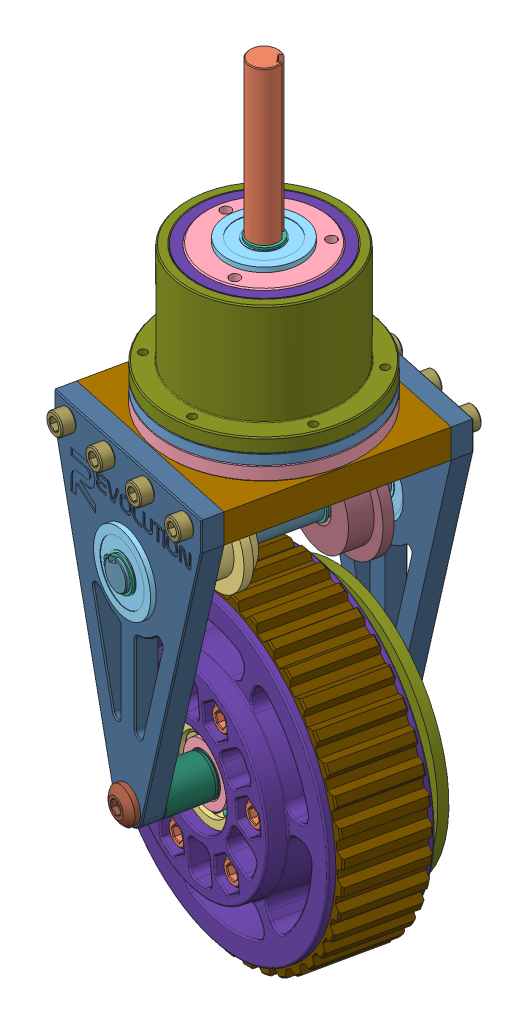
SolidWorks assembly Revolution 2 Plaction, configuration Default. Lengths in mm.
Overall size (163.7 274.4 125.67).
90 component instances, 35 part files, 0 mates.
Components (placement in the parent):
- cs_drive_hub_asm_1-1: cs_drive_hub_asm_1 [Default] at (28.1074 158.1318 104.3172) x (-0.796969 0 0.60402) z (-0.60402 0 -0.796969) size (89.7 127.05 89.7)
  - 5906K526_thrust_bushing_1-1: 5906K526_thrust_bushing_1 [Default] at (33.9501 -89.5224 3.5116) x (-0.279506 0 -0.960144) z (0 -1 0) size (63.5 63.5 3.17)
  - cs_vert_drive_shaft_1-1: cs_vert_drive_shaft_1 [Default] at (390.5574 -784.499 -2.4616) x (0 1 0) z (0.016748 0 0.99986) size (127.05 9.26 9.53)
  - 6843K12_miter_gear_1-1: 6843K12_miter_gear_1 [Default] at (36.0118 -122.8345 2.5948) x (-0.91373 0 0.406323) z (-0.406323 0 -0.91373) size (27.69 19.05 27.69)
  - revo2_pivot_hub-1: revo2_pivot_hub [Default] at (32.6196 -72.4841 4.7196) x (-0.740355 0 0.672216) z (-0.672216 0 -0.740355) size (63.5 46.42 63.5)
  - brf-06_1-1: brf-06_1 [Default] at (33.9501 -95.4787 3.5116) x (-0.582551 0 0.812794) z (0 -1 0) size (24.59 24.59 7.11)
  - brf-06_1-2: brf-06_1 [Default] at (33.9501 -53.0226 3.5116) x (-0.999614 0 -0.027772) z (0 1 0) size (24.59 24.59 7.11)
  - Imported_1-1: Imported_1 [Default] at (33.9501 -123.279 3.5116) x (0 -1 0) z (0.051397 0 0.998678) size (0.64 12.09 10.6)
  - Imported_1-2: Imported_1 [Default] at (33.9501 -49.0094 3.5116) x (0 1 0) z (0.82628 0 -0.563259) size (0.64 12.09 10.6)
  - large_thrust_bushing_1-1: large_thrust_bushing_1 [Default] at (33.9501 -102.2097 3.5116) x (1 0 0) z (0 -1 0) size (19.05 19.05 1.57)
  - bushing_backer_1-1: bushing_backer_1 [Default] at (33.9501 -99.0347 3.5116) x (1 0 0) z (0 -1 0) size (25.4 25.4 3.17)
- cs_wheel_box_asm_plaction-1: cs_wheel_box_asm_plaction [Default] at (-5.7354 51.1469 144.7113) x (0.977946 0 0.20886) z (0 1 0) size (149.25 84.94 179.3)
  - revo2_wheel_box_cap-1: revo2_wheel_box_cap [Default] at origin size (63.5 63.5 9.53)
  - 6843K12_miter_gear_1-1: 6843K12_miter_gear_1 [Default] at (1.3308 15.2099 -25.4535) x (-0.668029 0 0.744136) z (0.744136 0 0.668029) size (27.69 19.05 27.69)
  - revo2_side_plate-1: revo2_side_plate [Default] at (-18.57 61.2601 -1.4632) x (1 0 0) z (0 -1 0) size (63.5 106.45 6.35)
  - revo2_side_plate-2: revo2_side_plate [Default] at (18.217 -14.9399 -1.4632) x (-1 0 0) z (0 1 0) size (63.5 106.45 6.35)
  - BHCS_91255A535-1: BHCS_91255A535 [Default] at (-0.1765 -14.9399 -90.5764) x (1 0 0) z (0 -1 0) size (11.23 11.23 13.63)
  - 91251A192_shcs-1: 91251A192_shcs [Default] at (-25.5765 51.7351 4.7625) x (1 0 0) z (0 -1 0) size (6.86 6.86 13.9)
  - 91251A192_shcs-2: 91251A192_shcs [Default] at (25.2235 51.7351 4.7625) x (1 0 0) z (0 -1 0) size (6.86 6.86 13.9)
  - 91251A192_shcs-3: 91251A192_shcs [Default] at (-8.6423 51.7351 4.7665) x (1 0 0) z (0 -1 0) size (6.86 6.86 13.9)
  - 91251A192_shcs-4: 91251A192_shcs [Default] at (8.2893 -5.4149 4.7665) x (1 0 0) z (0 1 0) size (6.86 6.86 13.9)
  - 91251A192_shcs-5: 91251A192_shcs [Default] at (-25.5765 -5.4149 4.7625) x (1 0 0) z (0 1 0) size (6.86 6.86 13.9)
  - 91251A192_shcs-6: 91251A192_shcs [Default] at (25.2235 -5.4149 4.7625) x (1 0 0) z (0 1 0) size (6.86 6.86 13.9)
  - brf-06_1-1: brf-06_1 [Default] at (-0.1765 59.2789 -23.7744) x (1 0 0) z (0 1 0) size (24.59 24.59 7.11)
  - brf-06_1-2: brf-06_1 [Default] at (-0.1765 -12.9587 -23.7744) x (0.755419 0 -0.655243) z (0 -1 0) size (24.59 24.59 7.11)
  - 16t_ws_globe_gear-1: 16t_ws_globe_gear [Default] at (2.3218 39.2687 -25.5275) x (0.818565 0 -0.574414) z (0.574414 0 0.818565) size (35.31 10.29 35.31)
  - revo2_cross_drive_shaft-1: revo2_cross_drive_shaft [Default] at (136.4364 723.0009 -354.9485) x (0 -1 0) z (-0.924435 0 -0.381339) size (83.39 9.26 9.53)
  - Imported_1-1: Imported_1 [Default] at (-0.1765 -16.9719 -23.7744) x (0 1 0) z (0 0 1) size (0.64 12.09 10.6)
  - Imported_1-2: Imported_1 [Default] at (-0.1765 63.4318 -23.7744) x (0 -1 0) z (0 0 1) size (0.64 12.09 10.6)
  - large_thrust_bushing_1-1: large_thrust_bushing_1 [Default] at (-0.1765 -5.4149 -23.7744) x (1 0 0) z (0 1 0) size (19.05 19.05 1.57)
  - 91251A192_shcs-7: 91251A192_shcs [Default] at (8.2893 51.7351 4.7645) x (1 0 0) z (0 -1 0) size (6.86 6.86 13.9)
  - 91251A192_shcs-8: 91251A192_shcs [Default] at (-8.6423 -5.4149 4.7645) x (1 0 0) z (0 1 0) size (6.86 6.86 13.9)
  - Imported_1-3: Imported_1 [Default] at (-0.1765 15.6544 -23.7744) x (0 -1 0) z (0 0 1) size (0.64 12.09 10.6)
  - Imported_1-4: Imported_1 [Default] at (-0.1765 48.5474 -23.7744) x (0 -1 0) z (0 0 1) size (0.64 12.09 10.6)
  - Imported_1-5: Imported_1 [Default] at (-0.1765 37.3714 -23.7744) x (0 1 0) z (0 0 1) size (0.64 12.09 10.6)
  - BHCS_91255A535-2: BHCS_91255A535 [Default] at (-0.1765 61.2601 -90.5764) x (0.396029 0 -0.918238) z (0 1 0) size (11.23 11.23 13.63)
  - revo2_wheel_shaft-1: revo2_wheel_shaft [Default] at (-0.1765 -8.5899 -90.5764) x (0.571408 0 0.820666) z (0 1 0) size (12.7 12.7 63.5)
  - AM_36t_sprocket-1: AM_36t_sprocket [Default] at (-0.1765 48.1029 -90.5764) x (0.524782 0 0.851237) z (0 -1 0) size (82.55 82.55 3.1)
  - 4Plaction-500bearing-1: 4Plaction-500bearing [Default] at (-0.1765 3.3481 -90.5764) x (0 1 0) z (-0.599972 0 0.800021) size (41.66 115.7 115.7)
    - 4MW_d011-1: 4MW_d011 [Default] at origin size (22.87 98.05 98.05)
    - 4MW_d011-2: 4MW_d011 [Default] at (41.656 0 0) x (-1 0 0) z (0 0 -1) size (22.87 98.05 98.05)
    - 4RoughTread1-1: 4RoughTread1 [Default] at (8.128 0 0) x (0 -0.992815 0.119662) z (1 0 0) size (104 104 25.4)
    - 10-32_nylock_nut1-1: 10-32_nylock_nut1 [Default] at (130.8703 19.4882 -76.5177) x (0 -0.340837 0.940122) z (-1 0 0) size (11.68 10.93 7.15)
    - 10-32_nylock_nut1-2: 10-32_nylock_nut1 [Default] at (130.8703 76.0104 -21.3816) x (0 -0.984588 0.174888) z (-1 0 0) size (11.68 10.93 7.15)
    - 10-32_nylock_nut1-3: 10-32_nylock_nut1 [Default] at (130.8703 56.5222 55.1361) x (0 -0.643751 -0.765235) z (-1 0 0) size (11.68 10.93 7.15)
    - 10-32_nylock_nut1-4: 10-32_nylock_nut1 [Default] at (130.8703 -19.4882 76.5177) x (0 0.340837 -0.940122) z (-1 0 0) size (11.68 10.93 7.15)
    - 10-32_nylock_nut1-5: 10-32_nylock_nut1 [Default] at (130.8703 -76.0104 21.3816) x (0 0.984588 -0.174888) z (-1 0 0) size (11.68 10.93 7.15)
    - 10-32_nylock_nut1-6: 10-32_nylock_nut1 [Default] at (130.8703 -56.5222 -55.1361) x (0 0.643751 0.765235) z (-1 0 0) size (11.68 10.93 7.15)
    - 10-32x1375_shcs1-1: 10-32x1375_shcs1 [Default] at (1.5748 0 23.8125) x (0 -0.961068 -0.276312) z (0 0.276312 -0.961068) size (7.82 39.7 7.82)
    - 10-32x1375_shcs1-2: 10-32x1375_shcs1 [Default] at (1.5748 -20.6222 11.9062) x (0 -0.241241 -0.970465) z (0 0.970465 -0.241241) size (7.82 39.7 7.82)
    - 10-32x1375_shcs1-3: 10-32x1375_shcs1 [Default] at (1.5748 -20.6222 -11.9062) x (0 0.719827 -0.694154) z (0 0.694154 0.719827) size (7.82 39.7 7.82)
    - 10-32x1375_shcs1-4: 10-32x1375_shcs1 [Default] at (1.5748 0 -23.8125) x (0 0.961068 0.276312) z (0 -0.276312 0.961068) size (7.82 39.7 7.82)
    - 10-32x1375_shcs1-5: 10-32x1375_shcs1 [Default] at (1.5748 20.6222 -11.9062) x (0 0.241241 0.970465) z (0 -0.970465 0.241241) size (7.82 39.7 7.82)
    - 10-32x1375_shcs1-6: 10-32x1375_shcs1 [Default] at (1.5748 20.6222 11.9062) x (0 -0.719827 0.694154) z (0 -0.694154 -0.719827) size (7.82 39.7 7.82)
  - ball_bearing_60355K150-1: ball_bearing_60355K150 [Default] at (-0.1765 38.5271 -90.5764) x (1 0 0) z (0 1 0) size (28.57 28.57 6.35)
    - NONE-1: NONE [Default] at origin size (28.57 28.57 6.35)
    - NONEA-1: NONEA [Default] at origin size (18.68 18.68 6.35)
    - NONEB-1: NONEB [Default] at origin size (3.43 3.43 3.43)
    - NONEC-1: NONEC [Default] at origin size (3.43 3.43 3.43)
    - NONED-1: NONED [Default] at origin size (3.43 3.43 3.43)
    - NONEE-1: NONEE [Default] at origin size (3.43 3.43 3.43)
    - NONEF-1: NONEF [Default] at origin size (3.43 3.43 3.43)
    - NONEG-1: NONEG [Default] at origin size (3.43 3.43 3.43)
    - NONEH-1: NONEH [Default] at origin size (3.43 3.43 3.43)
    - NONEI-1: NONEI [Default] at origin size (3.43 3.43 3.43)
    - NONEJ-1: NONEJ [Default] at origin size (3.43 3.43 3.43)
    - NONEK-1: NONEK [Default] at origin size (3.43 3.43 3.43)
  - ball_bearing_60355K150-2: ball_bearing_60355K150 [Default] at (-0.1765 9.8251 -90.5764) x (1 0 0) z (0 1 0) size (28.57 28.57 6.35)
    - NONE-1: NONE [Default] at origin size (28.57 28.57 6.35)
    - NONEA-1: NONEA [Default] at origin size (18.68 18.68 6.35)
    - NONEB-1: NONEB [Default] at origin size (3.43 3.43 3.43)
    - NONEC-1: NONEC [Default] at origin size (3.43 3.43 3.43)
    - NONED-1: NONED [Default] at origin size (3.43 3.43 3.43)
    - NONEE-1: NONEE [Default] at origin size (3.43 3.43 3.43)
    - NONEF-1: NONEF [Default] at origin size (3.43 3.43 3.43)
    - NONEG-1: NONEG [Default] at origin size (3.43 3.43 3.43)
    - NONEH-1: NONEH [Default] at origin size (3.43 3.43 3.43)
    - NONEI-1: NONEI [Default] at origin size (3.43 3.43 3.43)
    - NONEJ-1: NONEJ [Default] at origin size (3.43 3.43 3.43)
    - NONEK-1: NONEK [Default] at origin size (3.43 3.43 3.43)
  - bushing_backer_1-1: bushing_backer_1 [Default] at (-0.1765 -5.4149 -23.7744) x (1 0 0) z (0 -1 0) size (25.4 25.4 3.17)
  - 90128A218-1: 90128A218 [Default] at (-22.1736 35.8601 14.097) size (7.92 7.92 14.58)
  - 90128A218-2: 90128A218 [Default] at (-22.1736 10.4601 14.097) x (0.5 0.866025 0) z (0 0 1) size (7.92 7.92 14.58)
  - 90128A218-3: 90128A218 [Default] at (-0.1765 -2.2399 14.097) x (-0.5 0.866025 0) z (0 0 1) size (7.92 7.92 14.58)
  - 90128A218-4: 90128A218 [Default] at (21.8205 10.4601 14.097) x (-1 0 0) z (0 0 1) size (7.92 7.92 14.58)
  - 90128A218-5: 90128A218 [Default] at (21.8205 35.8601 14.097) x (-0.5 -0.866025 0) z (0 0 1) size (7.92 7.92 14.58)
  - 90128A218-6: 90128A218 [Default] at (-0.1765 48.5601 14.097) x (0.5 -0.866025 0) z (0 0 1) size (7.92 7.92 14.58)
- bushing_hub_asm_1-1: bushing_hub_asm_1 [Default] at (11.3553 106.7094 120.0903) x (0.988095 0 -0.153847) z (-0.153847 0 -0.988095) size (63.5 38.1 63.5)
  - revo2_steering_hub_1-1: revo2_steering_hub_1 [Default] at origin size (63.5 38.1 63.5)
  - 1_1-1: 1_1 [Default] at (-0.595 0 0) size (44.45 38.1 44.45)
